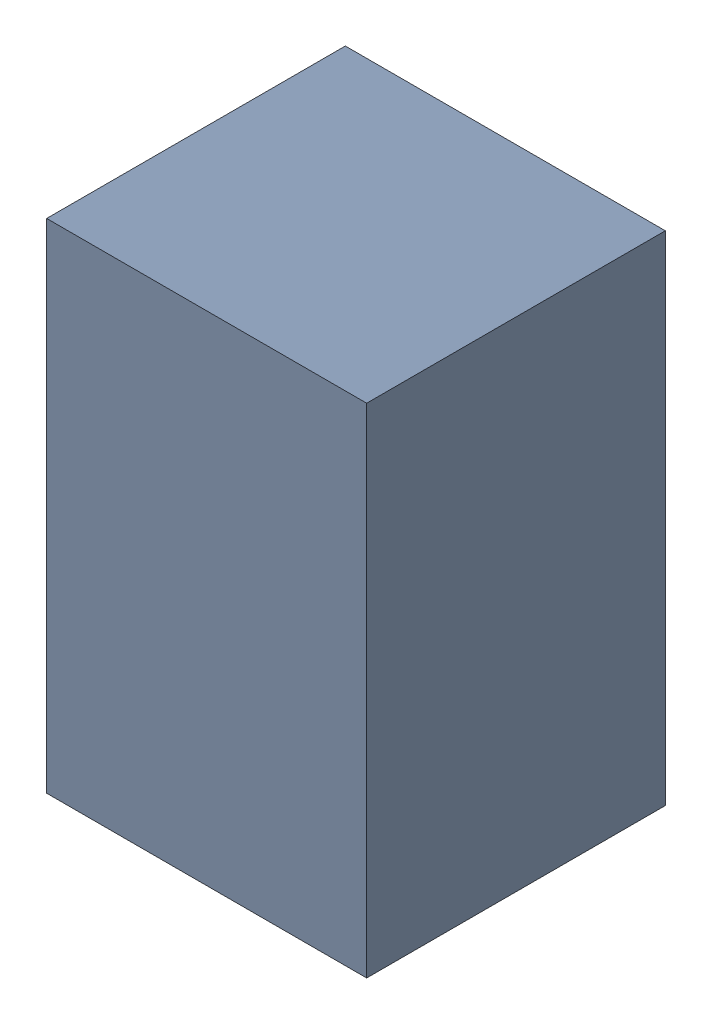
SolidWorks assembly C10, configuration Default. Lengths in mm.
Overall size (1.35 2.1 1.26).
2 component instances, 1 part files, 0 mates.
Components (placement in the parent):
- 407985696-1: 407985696 [Default] at (23.114 24.638 0.0127) size (1.35 2.1 1.26)
  - Extruded_1-1: Extruded_1 [Default] at origin size (1.35 2.1 1.26)
